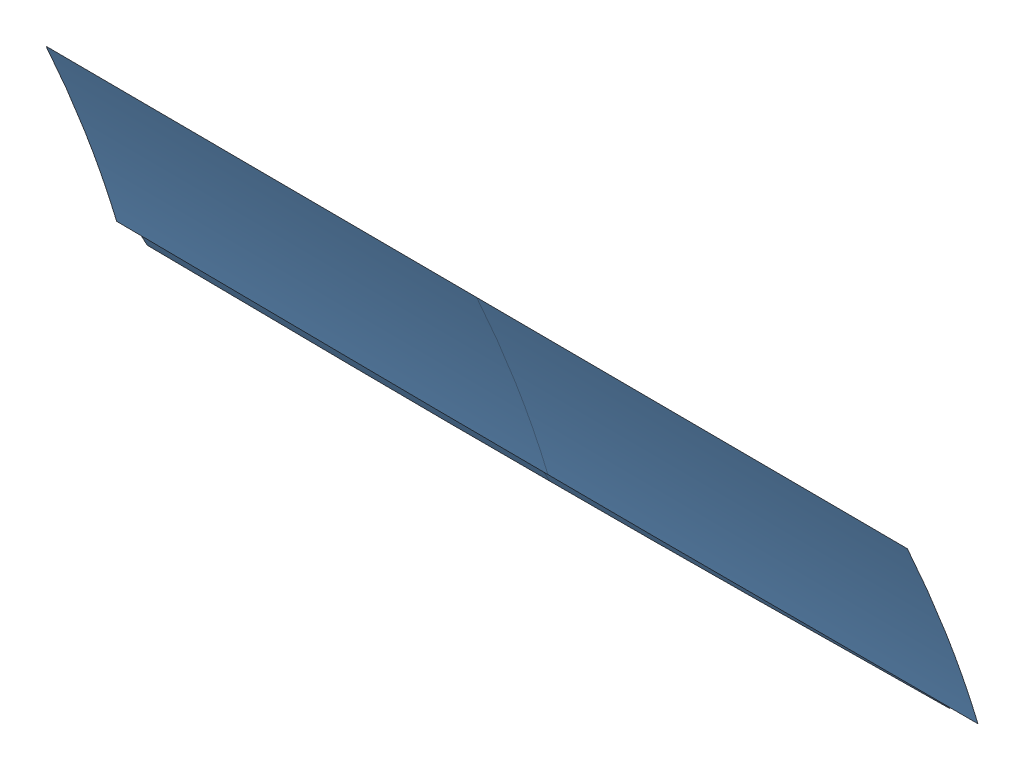
SolidWorks assembly gear_conection_V2, configuration Default. Lengths in mm.
Overall size (15.84 208.31 158.65).
2 component instances, 1 part files, 19 mates.
Components (placement in the parent):
- epifanies_katatomon-3: epifanies_katatomon [gear1] at (0 -75 0) x (-0.000308 -0.058747 -0.998273) z (0.999986 -0.005236 0) size (150 151.6 15)
- epifanies_katatomon-4: epifanies_katatomon [gear2] at (0 -73.4491 -17.5434) x (0 0.175434 -0.984491) z (1 0 0) size (50 51.63 13.97)
Mates (geometry in assembly coordinates):
- GearMate1: gear = 56.25 : 18.75 mm: line of epifanies_katatomon-4 through (1.5 25 0) axis (-1 0 0); line of epifanies_katatomon-3 through (1.5 -75.0052 0) axis (-0.999994 0.003491 0)
- Coincident8: coincident: line of assembly; line of assembly; line of epifanies_katatomon-4 through (1.5 25 0) axis (-1 0 0)
- Coincident9: coincident aligned: line of epifanies_katatomon-3 through (1.5 -75.0079 0) axis (-0.999986 0.005236 0)
- Coincident10: coincident: unknown of ?
- Coincident11: coincident: unknown of ?
- Tangent3: tangent: curve of epifanies_katatomon-3
- Tangent5: tangent: edge_curve of ?; edge_curve of ?
- Tangent6: tangent: edge_curve of ?; edge_curve of ?
- Tangent9: tangent: edge_curve of ?; edge_curve of ?
- Tangent10: tangent: curve of epifanies_katatomon-3; curve of epifanies_katatomon-4
- Coincident12: coincident: unknown of ?
- Tangent11: tangent: curve of epifanies_katatomon-3; curve of epifanies_katatomon-4
- Tangent13: tangent: edge_curve of ?; edge_curve of ?
- Angle1: planar angle = 0.017453 rad: line of assembly; line of assembly; line of epifanies_katatomon-3 through (0 -75 0) axis (0.00349 0.999842 -0.017452)
- Angle2: planar angle = 0.008727 rad anti-aligned: line of epifanies_katatomon-3 through (0 -75 0) axis (0.005236 0.999948 0.008727)
- Tangent14: tangent: edge_curve of ?; edge_curve of ?
- Tangent15: tangent: edge_curve of ?; edge_curve of ?
- Tangent16: tangent: edge_curve of ?; edge_curve of ?
- Tangent17: tangent: edge_curve of epifanies_katatomon-3; edge_curve of ?
